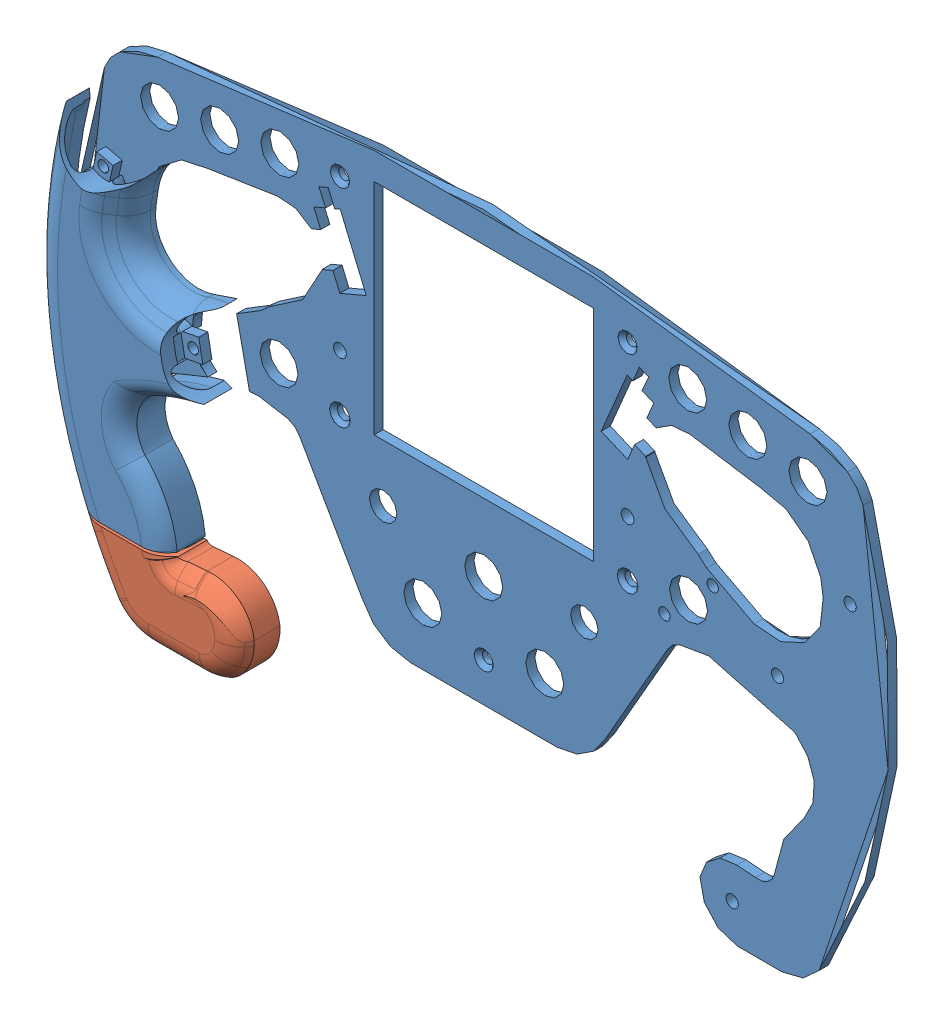
SolidWorks assembly right back grip assembly, configuration Default. Lengths in mm.
Overall size (68.83 153.47 34.79).
3 component instances, 3 part files, 11 mates.
Components (placement in the parent):
- left grip no ends or edges-1: left grip no ends or edges [Default] at (82.6904 40.4146 11.7802) size (272.22 167.67 14.17)
- bottom end-1: bottom end [Default] at (82.6904 40.4146 11.7802) size (55.53 45.36 15)
- top end back-2: top end back [Default] at (-37.1265 84.7585 12.7802) size (32.7 35.85 34.79)
Mates (geometry in assembly coordinates):
- Coincident1: coincident aligned: plane of left grip no ends or edges-1 through (82.6904 40.4146 11.7802) normal (0 0 -1); plane of bottom end-1 through (82.6904 40.4146 11.7802) normal (0 0 -1)
- Coincident2: coincident aligned: plane of left grip no ends or edges-1 through (82.6904 40.4146 11.7802) normal (0 0 -1); plane of top end-1 through (82.6904 40.4146 11.7802) normal (0 0 -1)
- Parallel1: parallel aligned: line of left grip no ends or edges-1 through (-16.1425 -18.1674 25.2802) axis (-1 0 0); line of bottom end-1 through (-16.0263 -19.0674 25.2802) axis (-1 0 0)
- Concentric3: concentric aligned: cylinder of left grip no ends or edges-1 through (116.1065 46.6634 26.7802) axis (0 0 -1) radius 169.0986; cylinder of bottom end-1 through (116.1065 46.6634 26.7802) axis (0 0 -1) radius 169.0986
- Concentric5: concentric aligned: cylinder of left grip no ends or edges-1 through (-16.4419 76.0793 26.7802) axis (0 0 -1) radius 33.4055; cylinder of top end-1 through (-16.4419 76.0793 26.7802) axis (0 0 -1) radius 33.4055
- Concentric6: concentric aligned: cylinder of left grip no ends or edges-1 through (116.1065 46.6634 26.7802) axis (0 0 -1) radius 167.5986; cylinder of top end-1 through (116.1065 46.6634 26.7802) axis (0 0 -1) radius 167.5986
- Parallel2: parallel: face of left grip no ends or edges-1; face of ?
- Coincident3: coincident aligned: plane of left grip no ends or edges-1 through (82.6904 40.4146 11.7802) normal (0 0 -1); plane of middle end-1 through (82.6904 40.4146 11.7802) normal (0 0 -1)
- Concentric7: concentric aligned: cylinder of left grip no ends or edges-1 through (13.752 -38.0168 26.7802) axis (0 0 -1) radius 67.615; cylinder of middle end-1 through (13.752 -38.0168 26.7802) axis (0 0 -1) radius 67.615
- Concentric8: concentric: cylinder of left grip no ends or edges-1 through (-35.1709 77.1534 25.9478) axis (0 0 -1) radius 1.75; cylinder of top end back-2 through (-35.1709 77.1534 -36.3558) axis (0 0 -1) radius 1.75
- Coincident4: coincident: plane of left grip no ends or edges-1 through (-37.3165 80.1979 15.7802) normal (0 0 -1); plane of top end-2 through (-28.8754 76.0219 15.7802) normal (0 0 1)
